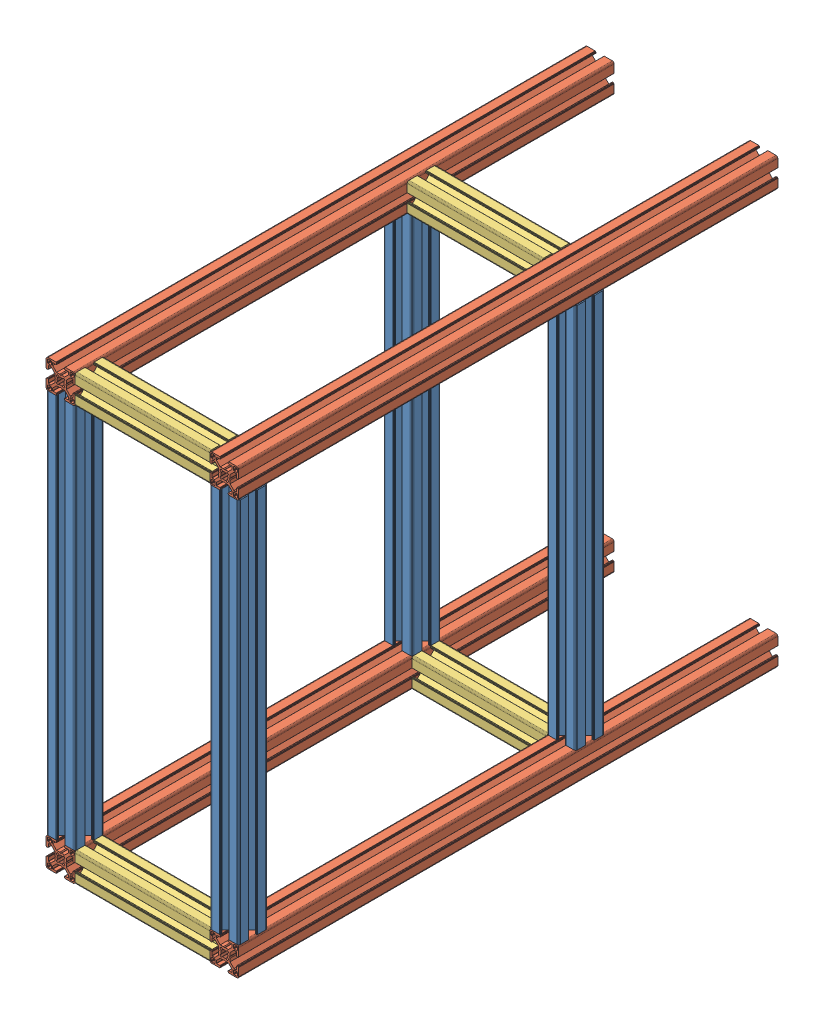
SolidWorks assembly module2_frame_v1.0, configuration Default. Lengths in mm.
Overall size (200 460 560).
12 component instances, 3 part files, 34 mates.
Components (placement in the parent):
- Profile_30x30mm_400mm-1: Profile_30x30mm_400mm [Default] x (1 0 0) z (0 -1 0) size (30 30 400)
- Profile_30x30mm_400mm-3: Profile_30x30mm_400mm [Default] at (-170 0 0) x (1 0 0) z (0 -1 0) size (30 30 400)
- profile_30x30mm_560mm-8: profile_30x30mm_560mm [Default] at (0 -30 30) size (30 30 560)
- profile_30x30mm_560mm-10: profile_30x30mm_560mm [Default] at (-170 -30 30) size (30 30 560)
- profile_30x30mm_560mm-6: profile_30x30mm_560mm [Default] at (-170 400 30) size (30 30 560)
- Profile_30x30mm_400mm-4: Profile_30x30mm_400mm [Default] at (30 400 -350) x (-1 0 0) z (0 1 0) size (30 30 400)
- profile_30x30mm_560mm-9: profile_30x30mm_560mm [Default] at (0 400 30) size (30 30 560)
- Profile_30x30mm_140mm-5: Profile_30x30mm_140mm [Default] at (0 400 30) x (0 0 -1) z (1 0 0) size (30 30 140)
- Profile_30x30mm_140mm-4: Profile_30x30mm_140mm [Default] at (0 400 -315) x (0 0 -1) z (1 0 0) size (30 30 140)
- Profile_30x30mm_140mm-7: Profile_30x30mm_140mm [Default] at (0 0 30) x (0 -1 0) z (1 0 0) size (30 30 140)
- Profile_30x30mm_140mm-9: Profile_30x30mm_140mm [Default] at (0 -30 -320) x (0 0 -1) z (1 0 0) size (30 30 140)
- Profile_30x30mm_400mm-5: Profile_30x30mm_400mm [Default] at (-170 0 -350) x (1 0 0) z (0 -1 0) size (30 30 400)
Mates (geometry in assembly coordinates):
- Coincident1: coincident: plane of assembly; plane of assembly; plane of Profile_30x30mm_400mm-1 through (0 400 0) normal (0 1 0); plane of Profile_30x30mm_400mm-3 through (-170 400 0) normal (0 1 0)
- Coincident7: coincident: plane of assembly; plane of assembly; plane of Profile_30x30mm_400mm-1 through (10.25 400 30) normal (0 0 1); plane of Profile_30x30mm_400mm-3 through (-142 400 30) normal (0 0 1)
- Coincident25: coincident: plane of assembly; plane of assembly; plane of profile_30x30mm_560mm-8 through (0 -30 30) normal (0 0 1); plane of profile_30x30mm_560mm-10 through (-170 -30 30) normal (0 0 1)
- Coincident26: coincident: plane of assembly; plane of assembly; plane of profile_30x30mm_560mm-10 through (-170 -30 30) normal (0 0 1); plane of profile_30x30mm_560mm-6 through (-170 400 30) normal (0 0 1)
- Coincident27: coincident: plane of assembly; plane of assembly; plane of profile_30x30mm_560mm-10 through (-140 -10.25 -530) normal (1 0 0); plane of profile_30x30mm_560mm-6 through (-140 419.75 -530) normal (1 0 0)
- Coincident30: coincident: plane of assembly; plane of assembly; plane of profile_30x30mm_560mm-8 through (10.25 0 -530) normal (0 1 0); plane of profile_30x30mm_560mm-10 through (-159.75 0 -530) normal (0 1 0)
- Coincident32: coincident: plane of assembly; plane of assembly; plane of Profile_30x30mm_400mm-1 through (30 400 2) normal (1 0 0); plane of profile_30x30mm_560mm-8 through (30 -28 -530) normal (1 0 0)
- Coincident35: coincident: plane of assembly; plane of assembly; plane of Profile_30x30mm_400mm-3 through (-170 400 10.25) normal (-1 0 0); plane of profile_30x30mm_560mm-6 through (-170 428 -530) normal (-1 0 0)
- Coincident69: coincident: plane of assembly through (0 0 0) normal (0 1 0); plane of Profile_30x30mm_400mm-1 through (0 0 0) normal (0 -1 0); plane of assembly
- Coincident70: coincident: plane of assembly through (0 0 0) normal (0 0 1); plane of Profile_30x30mm_400mm-1 through (0 0 0) normal (0 0 1); plane of assembly
- Coincident71: coincident: plane of assembly through (0 0 0) normal (1 0 0); plane of Profile_30x30mm_400mm-1 through (0 0 0) normal (1 0 0); plane of assembly
- Coincident81: coincident: plane of assembly; plane of assembly; plane of Profile_30x30mm_400mm-1 through (30 400 19.75) normal (1 0 0); plane of profile_30x30mm_560mm-9 through (30 419.75 -530) normal (1 0 0)
- Distance36: distance = 30 mm: plane of assembly; plane of assembly; plane of Profile_30x30mm_400mm-1 through (0 0 0) normal (0 -1 0); plane of profile_30x30mm_560mm-8 through (19.75 -30 -530) normal (0 -1 0)
- Distance37: distance = 30 mm: plane of assembly; plane of assembly; plane of Profile_30x30mm_400mm-1 through (19.75 400 0) normal (0 0 -1); plane of profile_30x30mm_560mm-8 through (0 -30 30) normal (0 0 1)
- Distance38: distance = 30 mm: plane of assembly; plane of assembly; plane of Profile_30x30mm_400mm-1 through (19.75 400 0) normal (0 0 -1); plane of profile_30x30mm_560mm-9 through (0 400 30) normal (0 0 1)
- Distance39: distance = 30 mm: plane of assembly; plane of assembly; plane of Profile_30x30mm_400mm-3 through (-170 400 0) normal (0 1 0); plane of profile_30x30mm_560mm-6 through (-142 430 -530) normal (0 1 0)
- Distance40: distance = 30 mm: plane of assembly; plane of assembly; plane of Profile_30x30mm_400mm-1 through (0 400 0) normal (0 1 0); plane of profile_30x30mm_560mm-9 through (10.25 430 -530) normal (0 1 0)
- Coincident114: coincident: plane of profile_30x30mm_560mm-8 through (28 0 -530) normal (0 1 0); plane of ? through (22.2507 -5.7283 -380) normal (0 -1 0)
- Coincident115: coincident: plane of profile_30x30mm_560mm-8 through (30 -10.25 -530) normal (1 0 0); plane of ? through (22.2507 -5.7283 -369.75) normal (1 0 0)
- Coincident118: coincident: point of assembly; plane of assembly; point of Profile_30x30mm_140mm-5; plane of Profile_30x30mm_140mm-4 through (-140 400 -315) normal (-1 0 0)
- Coincident119: coincident: plane of assembly; plane of assembly; plane of Profile_30x30mm_140mm-5 through (-140 400 30) normal (-1 0 0); plane of Profile_30x30mm_140mm-4 through (-140 400 -315) normal (-1 0 0)
- Coincident120: coincident: plane of assembly; plane of assembly; plane of profile_30x30mm_560mm-6 through (-140 419.75 -530) normal (1 0 0); plane of Profile_30x30mm_140mm-4 through (-140 400 -315) normal (-1 0 0)
- Coincident123: coincident: plane of assembly; plane of assembly; plane of Profile_30x30mm_140mm-5 through (-140 400 28) normal (0 -1 0); plane of Profile_30x30mm_140mm-4 through (-140 400 -334.75) normal (0 -1 0)
- Coincident126: coincident: plane of assembly; plane of assembly; plane of profile_30x30mm_560mm-6 through (-159.75 430 -530) normal (0 1 0); plane of Profile_30x30mm_140mm-4 through (-140 430 -325.25) normal (0 1 0)
- Coincident141: coincident: plane of assembly; plane of assembly; plane of Profile_30x30mm_140mm-7 through (-140 -19.75 30) normal (0 0 1); plane of profile_30x30mm_560mm-10 through (-170 -30 30) normal (0 0 1)
- Coincident142: coincident: plane of assembly; plane of assembly; plane of profile_30x30mm_560mm-10 through (-168 -30 -530) normal (0 -1 0); plane of Profile_30x30mm_140mm-7 through (-140 -30 28) normal (0 -1 0)
- Coincident143: coincident: plane of assembly; plane of assembly; plane of profile_30x30mm_560mm-10 through (-140 -28 -530) normal (1 0 0); plane of Profile_30x30mm_140mm-7 through (-140 0 30) normal (-1 0 0)
- Distance45: distance = 185 mm: plane of assembly; plane of assembly; plane of Profile_30x30mm_140mm-4 through (-140 419.75 -345) normal (0 0 -1); plane of profile_30x30mm_560mm-6 through (-170 400 -530) normal (0 0 -1)
- Coincident163: coincident: plane of assembly; plane of assembly; plane of profile_30x30mm_560mm-10 through (-140 -10.25 -530) normal (1 0 0); plane of Profile_30x30mm_140mm-9 through (-140 -30 -320) normal (-1 0 0)
- Distance50: distance = 180 mm: plane of assembly; plane of assembly; plane of Profile_30x30mm_140mm-9 through (-140 -28 -350) normal (0 0 -1); plane of profile_30x30mm_560mm-10 through (-170 -30 -530) normal (0 0 -1)
- Coincident186: coincident: plane of assembly; plane of assembly; plane of profile_30x30mm_560mm-10 through (-142 0 -530) normal (0 1 0); plane of Profile_30x30mm_400mm-5 through (-170 0 -350) normal (0 -1 0)
- Coincident187: coincident: plane of assembly; plane of assembly; plane of profile_30x30mm_560mm-10 through (-170 -2 -530) normal (-1 0 0); plane of Profile_30x30mm_400mm-5 through (-170 400 -339.75) normal (-1 0 0)
- Coincident188: coincident: plane of assembly; plane of assembly; plane of Profile_30x30mm_140mm-9 through (-140 -19.75 -320) normal (0 0 1); plane of Profile_30x30mm_400mm-5 through (-142 400 -320) normal (0 0 1)
- Coincident189: coincident: plane of assembly; plane of assembly; plane of Profile_30x30mm_400mm-4 through (2 0 -320) normal (0 0 1); plane of Profile_30x30mm_140mm-9 through (-140 -19.75 -320) normal (0 0 1)
